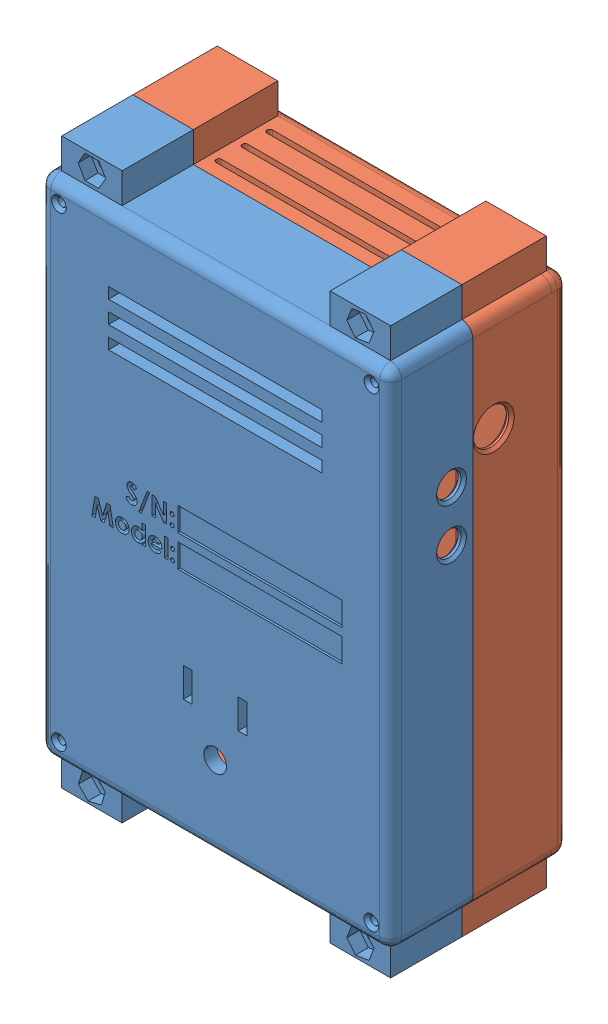
SolidWorks assembly Enclosure, configuration Default. Lengths in mm.
Overall size (81.28 130.84 41.15).
2 component instances, 2 part files, 3 mates.
Components (placement in the parent):
- back-1: back [Default] at (29.377 61.845 96.6049) size (81.28 130.84 19.05)
- front-1: front [Default] at (29.377 61.845 71.9669) x (-1 0 0) z (0 0 -1) size (81.28 130.84 24.13)
Mates (geometry in assembly coordinates):
- Coincident10: coincident anti-aligned: plane of back-1 through (29.377 61.845 90.2549) normal (0 0 -1); plane of front-1 through (29.377 61.845 90.2549) normal (0 0 1)
- Coincident11: coincident aligned: circle of back-1; circle of front-1
- Coincident12: coincident aligned: circle of back-1; circle of front-1
